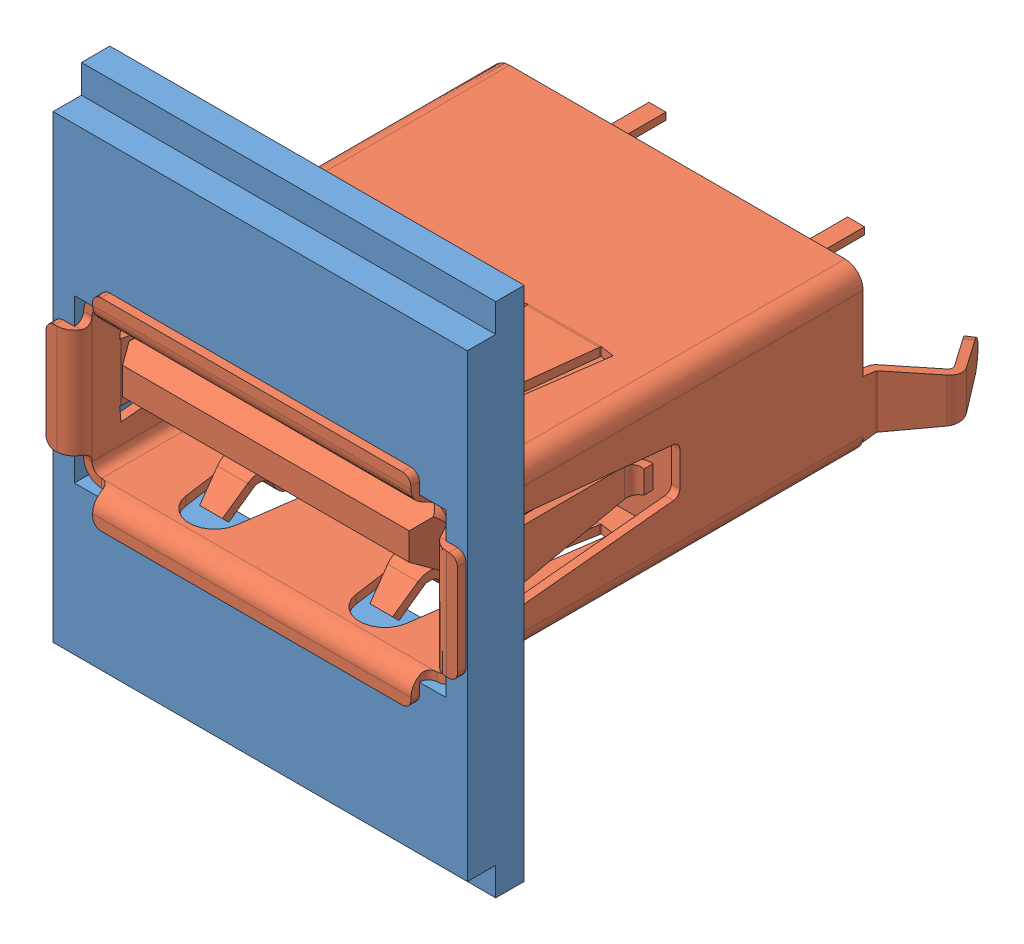
SolidWorks assembly Keystone-USB2-A, configuration Standard. Lengths in mm.
Overall size (15.8 18.2 18.93).
2 component instances, 2 part files, 6 mates.
Components (placement in the parent):
- Keystone-USB-2-Pannel-1: Keystone-USB-2-Pannel [Standard] at (-14.6 -17.2 0) x (-1 0 0) z (0 0 -1) size (14.6 18.2 2)
- 96939-1: 96939 [Standard] at (-7.3 -9.1 0.3) size (15.8 7.12 18.93)
Mates (geometry in assembly coordinates):
- Deckungsgleich1: coincident aligned: plane of Keystone-USB-2-Pannel-1 through (-14.6 -17.2 0) normal (0 0 1); plane of assembly through (0 0 0) normal (0 0 1)
- Deckungsgleich2: coincident aligned: plane of Keystone-USB-2-Pannel-1 through (0 0 -2) normal (0 1 0); plane of assembly through (0 0 0) normal (0 1 0)
- Deckungsgleich3: coincident aligned: plane of Keystone-USB-2-Pannel-1 through (0 -17.2 -1) normal (1 0 0); plane of assembly through (0 0 0) normal (1 0 0)
- Deckungsgleich4: coincident: plane of Keystone-USB-2-Pannel-1 through (-13.85 -6.24 -10) normal (0 -1 0); plane of 96939-1 through (-13.85 -6.24 -14.7) normal (0 1 0)
- Deckungsgleich5: coincident: plane of Keystone-USB-2-Pannel-1 through (-14.6 -17.2 0) normal (0 0 1); plane of 96939-1 through (-13.212 -5.92 0) normal (0 0 -1)
- Deckungsgleich6: coincident anti-aligned: plane of Keystone-USB-2-Pannel-1 through (-0.75 -6.24 -10) normal (-1 0 0); plane of 96939-1 through (-0.75 -9.1 0.3) normal (1 0 0)
